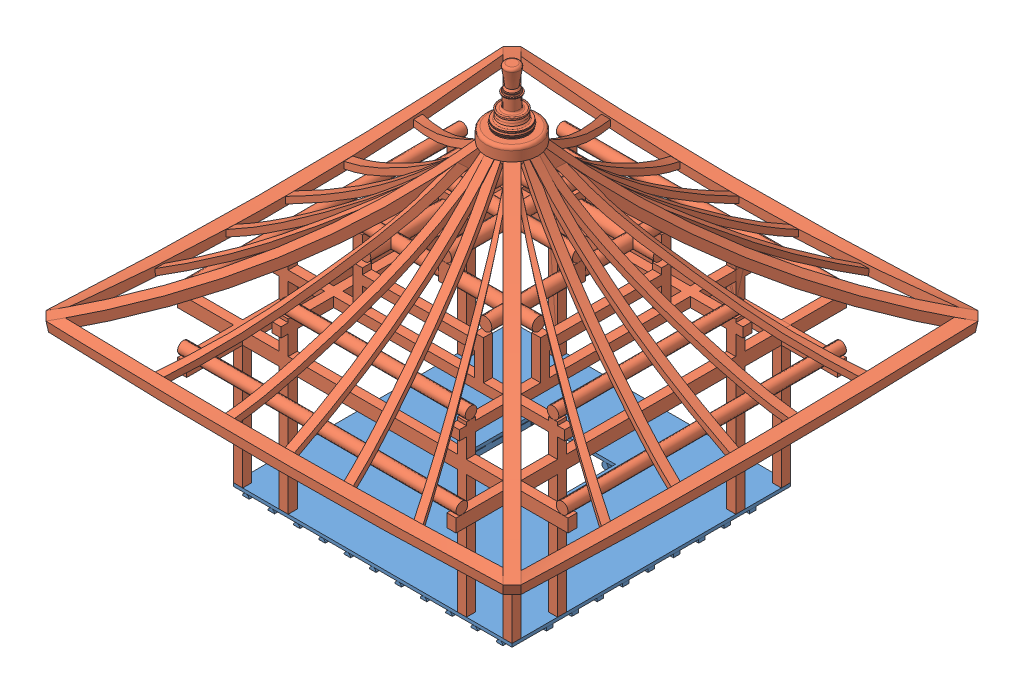
SolidWorks assembly 装配体2, configuration 默认. Lengths in mm.
Overall size (7303.6 5740 7303.6).
2 component instances, 2 part files, 3 mates.
Components (placement in the parent):
- 隔板儿层-1: 隔板儿层 [默认] at (-2139.2547 26.3665 2140) size (4280 150 4280)
- 三层梁柱-1: 三层梁柱 [默认] at (-2139.2547 76.3665 2140) size (7303.6 5590 7303.6)
Mates (geometry in assembly coordinates):
- 重合1: coincident: plane of 隔板儿层-1 through (-2049.2547 76.3665 2020) normal (-1 0 0); plane of 三层梁柱-1 through (-2049.2547 176.3665 2120) normal (-1 0 0)
- 重合2: coincident: plane of 隔板儿层-1 through (-2139.2547 76.3665 2140) normal (0 1 0); plane of 三层梁柱-1 through (2140.7453 76.3665 -2140) normal (0 -1 0)
- 重合3: coincident: plane of 隔板儿层-1 through (-2089.2547 76.3665 2120) normal (0 0 -1); plane of 三层梁柱-1 through (-2089.2547 176.3665 2120) normal (0 0 -1)
